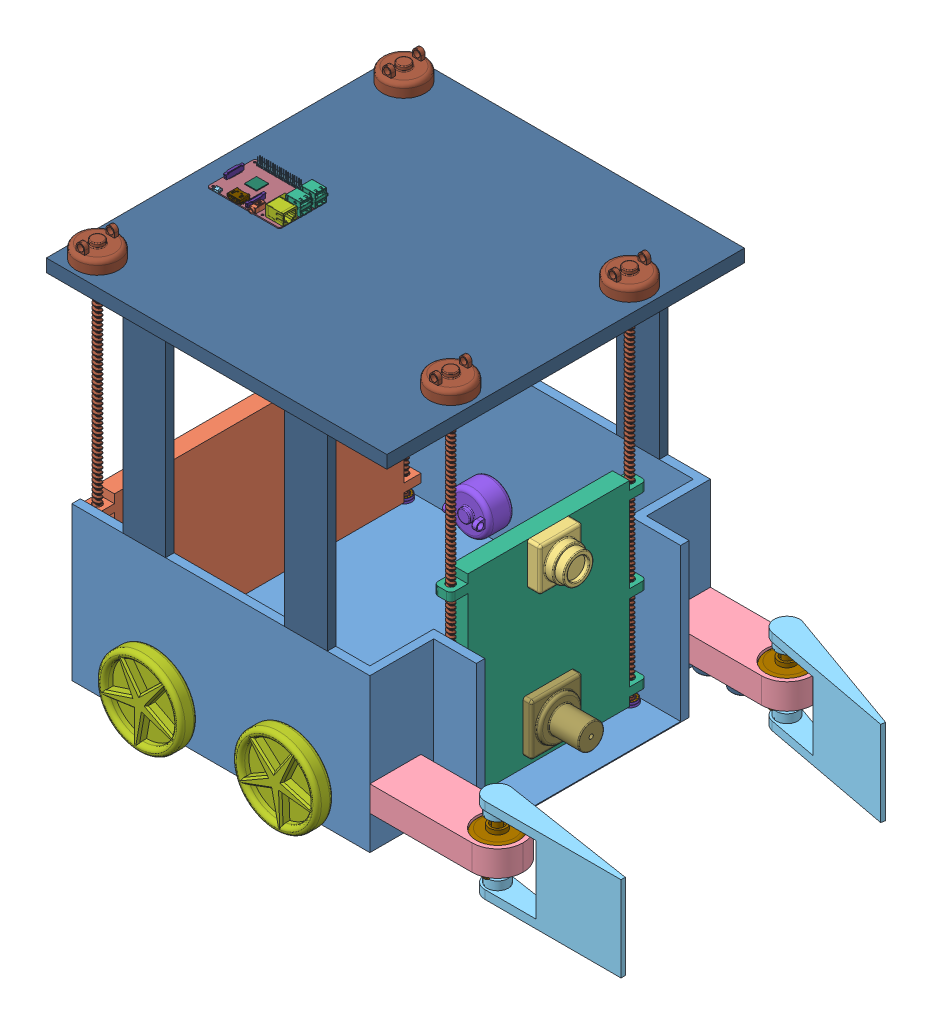
SolidWorks assembly BOT, configuration Default. Lengths in mm.
Overall size (650 473.67 464.94).
118 component instances, 28 part files, 77 mates.
Components (placement in the parent):
- Base-1: Base [Default] at origin size (400 180 400)
- Back-1: Back [Default] at (-175 95.5 0) size (20 179 380)
- Camera-2: Camera [Default] at (185 211 0) size (35 50 50)
- EP-1: EP [Default] at (175 55 170) size (150 30 60)
- EP-2: EP [Default] at (175 55 -170) size (150 30 60)
- Flap-1: Flap [Default] at (295 5 170) size (175 100 30)
- Flap-2: Flap [Default] at (295 5 -170) x (0.982637 0 0.185541) z (-0.185541 0 0.982637) size (175 100 30)
- Front-1: Front [Default] at (165 121 0) size (20 230 230)
- Wheel-1: Wheel [Default] at (-65 47 232) x (-0.85503 -0.518579 0) z (0 0 -1) size (100 100 25.47)
- Wheel-2: Wheel [Default] at (95 47 232) x (-0.730595 -0.682811 0) z (0 0 -1) size (100 100 25.47)
- Wheel-3: Wheel [Default] at (95 47 -232) x (0.960603 -0.277926 0) z (0 0 1) size (100 100 25.47)
- Wheel-4: Wheel [Default] at (-65 47 -232) x (0.992245 -0.124298 0) z (0 0 1) size (100 100 25.47)
- Motor-1: Motor [Default] at (-65 47 155) x (0 1 0) z (0 0 1) size (50 50 70)
- Motor-2: Motor [Default] at (95 47 155) x (0 -1 0) z (0 0 1) size (50 50 70)
- Motor-3: Motor [Default] at (95 47 -155) x (0 -1 0) z (0 0 -1) size (50 50 70)
- Motor-4: Motor [Default] at (-65 47 -155) x (0 -1 0) z (0 0 -1) size (50 50 70)
- Motor Double-1: Motor Double [Default] at (295 40 170) x (0.968172 0 -0.250286) z (0 1 0) size (50 50 70)
- Motor Double-2: Motor Double [Default] at (295 40 -170) x (1 0 0) z (0 1 0) size (50 50 70)
- Part Base-1: Part Base [Default] at (5 410 0) size (400 245 420)
- Motor Long-1: Motor Long [Default] at (175 440 -105) x (-1 0 0) z (0 -1 0) size (50 50 448)
- Motor Long-2: Motor Long [Default] at (-165 440 180) x (-1 0 0) z (0 -1 0) size (50 50 448)
- Motor Long-3: Motor Long [Default] at (-165 440 -180) x (-1 0 0) z (0 -1 0) size (50 50 448)
- Motor Long-4: Motor Long [Default] at (175 440 105) x (-1 0 0) z (0 -1 0) size (50 50 448)
- LIDAR-1: LIDAR [Default] at (185 48 0) size (50 60 60)
- RaspberryPi-1: RaspberryPi [Default] at (-127.6161 428.3 18) size (89.62 18.75 58.3)
  - RaspberryPi(2)^RaspberryPi-1: RaspberryPi(2)^RaspberryPi [Default] at origin size (89.62 18.75 58.3) (virtual)
    - Mainboard2^RaspberryPi(2)_RaspberryPi-1: Mainboard2^RaspberryPi(2)_RaspberryPi [Default] at origin size (85 1.3 56) (virtual)
    - GPIO^RaspberryPi(2)_RaspberryPi-1: GPIO^RaspberryPi(2)_RaspberryPi [Default] at (-11.37 0 -24.5) x (0 0 1) z (-1 0 0) size (5 11.5 50.8) (virtual)
    - Processor^RaspberryPi(2)_RaspberryPi-1: Processor^RaspberryPi(2)_RaspberryPi [Default] at (-15.5 0 -3) x (0 0 1) z (-1 0 0) size (14 1 14) (virtual)
    - GPU^RaspberryPi(2)_RaspberryPi-1: GPU^RaspberryPi(2)_RaspberryPi [Default] at (15.25 0 -5.75) x (0 0 1) z (-1 0 0) size (9.1 1 9.1) (virtual)
    - CameraAssembly^RaspberryPi(2)_RaspberryPi-1: CameraAssembly^RaspberryPi(2)_RaspberryPi [Default] at (10.0885 -2.9159 16.55) x (-1 0 0) z (0 0 -1) size (5.01 5.51 22.11) (virtual)
    - CameraAssembly^RaspberryPi(2)_RaspberryPi-2: CameraAssembly^RaspberryPi(2)_RaspberryPi [Default] at (-46.3885 -2.9159 0) size (5.01 5.51 22.11) (virtual)
    - HDMI^RaspberryPi(2)_RaspberryPi-1: HDMI^RaspberryPi(2)_RaspberryPi [Default] at (-10.2 0.27 29.3) size (15.04 8.38 12.15) (virtual)
    - RAM^RaspberryPi(2)_RaspberryPi-1: RAM^RaspberryPi(2)_RaspberryPi [Default] at (0.5 -2.3 -6) x (0 0 1) z (-1 0 0) size (12 1 12) (virtual)
    - Audio^RaspberryPi(2)_RaspberryPi-1: Audio^RaspberryPi(2)_RaspberryPi [Default] at (10.9 0.15 21.75) size (7 6 14.8) (virtual)
    - MicroSDSocket^RaspberryPi(2)_RaspberryPi-1: MicroSDSocket^RaspberryPi(2)_RaspberryPi [Default] at (-34.5 -1.3 -0.7) x (0 0 -1) z (-1 0 0) size (13 1.3 14) (virtual)
    - MicroSD^RaspberryPi(2)_RaspberryPi-1: MicroSD^RaspberryPi(2)_RaspberryPi [Default] at (-37 -2.3 0.1) x (0 0 1) z (-1 0 0) size (11.01 1 15) (virtual)
    - micro USB2^RaspberryPi(2)_RaspberryPi-1: micro USB2^RaspberryPi(2)_RaspberryPi [Default] at (-17.2704 -5.0969 44.9026) size (7.98 2.93 5.58) (virtual)
    - usb double^RaspberryPi(2)_RaspberryPi-1: usb double^RaspberryPi(2)_RaspberryPi [Default] at (30.38 -0.09 -18.85) x (0 0 -1) z (1 0 0) size (15.6 18.75 17.92) (virtual)
    - usb double^RaspberryPi(2)_RaspberryPi-2: usb double^RaspberryPi(2)_RaspberryPi [Default] at (30.38 -0.09 -1.25) x (0 0 -1) z (1 0 0) size (15.6 18.75 17.92) (virtual)
    - RJ45-LED^RaspberryPi(2)_RaspberryPi-1: RJ45-LED^RaspberryPi(2)_RaspberryPi [Default] at (34.11 7.4 17.348) x (1 0 0) z (0 -1 0) size (21.3 18 14.1) (virtual)
- Bearing-1: Bearing [Default] at (-165 1 -180) size (18 5 18)
  - Bearing ring-2: Bearing ring [Default] at origin size (18 5 18)
  - Bearing roller-16: Bearing roller [Default] at (6.5617 0.5 -1.5833) x (-0.193213 0 -0.981157) z (0.981157 0 -0.193213) size (2.5 4.5 2.5)
  - Bearing roller-17: Bearing roller [Default] at (5.5466 0.5 -3.8467) x (-0.5346 0 -0.845105) z (0.845105 0 -0.5346) size (2.5 4.5 2.5)
  - Bearing roller-18: Bearing roller [Default] at (3.7825 0.5 -5.5906) x (-0.803787 0 -0.594917) z (0.594917 0 -0.803787) size (2.5 4.5 2.5)
  - Bearing roller-19: Bearing roller [Default] at (1.5075 0.5 -6.5795) x (-0.964418 0 -0.264382) z (0.264382 0 -0.964418) size (2.5 4.5 2.5)
  - Bearing roller-20: Bearing roller [Default] at (-0.9711 0.5 -6.6798) x (-0.994799 0 0.101859) z (-0.101859 0 -0.994799) size (2.5 4.5 2.5)
  - Bearing roller-21: Bearing roller [Default] at (-3.3185 0.5 -5.8779) x (-0.890827 0 0.454343) z (-0.454343 0 -0.890827) size (2.5 4.5 2.5)
  - Bearing roller-22: Bearing roller [Default] at (-5.2178 0.5 -4.2822) x (-0.666544 0 0.745466) z (-0.745466 0 -0.666544) size (2.5 4.5 2.5)
  - Bearing roller-23: Bearing roller [Default] at (-6.4124 0.5 -2.1081) x (-0.35224 0 0.93591) z (-0.93591 0 -0.35224) size (2.5 4.5 2.5)
  - Bearing roller-24: Bearing roller [Default] at (-6.7409 0.5 0.3506) x (0.009636 0 0.999954) z (-0.999954 0 0.009636) size (2.5 4.5 2.5)
  - Bearing roller-25: Bearing roller [Default] at (-6.159 0.5 2.762) x (0.37021 0 0.928948) z (-0.928948 0 0.37021) size (2.5 4.5 2.5)
  - Bearing roller-26: Bearing roller [Default] at (-4.7454 0.5 4.8004) x (0.680785 0 0.732483) z (-0.732483 0 0.680785) size (2.5 4.5 2.5)
  - Bearing roller-27: Bearing roller [Default] at (-2.6908 0.5 6.1905) x (0.899417 0 0.437092) z (-0.437092 0 0.899417) size (2.5 4.5 2.5)
  - Bearing roller-28: Bearing roller [Default] at (-0.2728 0.5 6.7445) x (0.996577 0 0.082669) z (-0.082669 0 0.996577) size (2.5 4.5 2.5)
  - Bearing roller-29: Bearing roller [Default] at (2.182 0.5 6.3876) x (0.959144 0 -0.282918) z (0.282918 0 0.959144) size (2.5 4.5 2.5)
  - Bearing roller-30: Bearing roller [Default] at (4.3421 0.5 5.168) x (0.792173 0 -0.610296) z (0.610296 0 0.792173) size (2.5 4.5 2.5)
  - Bearing roller-31: Bearing roller [Default] at (5.9158 0.5 3.2505) x (0.518215 0 -0.85525) z (0.85525 0 0.518215) size (2.5 4.5 2.5)
  - Bearing roller-32: Bearing roller [Default] at (6.6905 0.5 0.894) x (0.174269 0 -0.984698) z (0.984698 0 0.174269) size (2.5 4.5 2.5)
- Bearing-2: Bearing [Default] at (175 1 105) size (18 5 18)
  - Bearing ring-2: Bearing ring [Default] at origin size (18 5 18)
  - Bearing roller-16: Bearing roller [Default] at (6.5617 0.5 -1.5833) x (-0.193213 0 -0.981157) z (0.981157 0 -0.193213) size (2.5 4.5 2.5)
  - Bearing roller-17: Bearing roller [Default] at (5.5466 0.5 -3.8467) x (-0.5346 0 -0.845105) z (0.845105 0 -0.5346) size (2.5 4.5 2.5)
  - Bearing roller-18: Bearing roller [Default] at (3.7825 0.5 -5.5906) x (-0.803787 0 -0.594917) z (0.594917 0 -0.803787) size (2.5 4.5 2.5)
  - Bearing roller-19: Bearing roller [Default] at (1.5075 0.5 -6.5795) x (-0.964418 0 -0.264382) z (0.264382 0 -0.964418) size (2.5 4.5 2.5)
  - Bearing roller-20: Bearing roller [Default] at (-0.9711 0.5 -6.6798) x (-0.994799 0 0.101859) z (-0.101859 0 -0.994799) size (2.5 4.5 2.5)
  - Bearing roller-21: Bearing roller [Default] at (-3.3185 0.5 -5.8779) x (-0.890827 0 0.454343) z (-0.454343 0 -0.890827) size (2.5 4.5 2.5)
  - Bearing roller-22: Bearing roller [Default] at (-5.2178 0.5 -4.2822) x (-0.666544 0 0.745466) z (-0.745466 0 -0.666544) size (2.5 4.5 2.5)
  - Bearing roller-23: Bearing roller [Default] at (-6.4124 0.5 -2.1081) x (-0.35224 0 0.93591) z (-0.93591 0 -0.35224) size (2.5 4.5 2.5)
  - Bearing roller-24: Bearing roller [Default] at (-6.7409 0.5 0.3506) x (0.009636 0 0.999954) z (-0.999954 0 0.009636) size (2.5 4.5 2.5)
  - Bearing roller-25: Bearing roller [Default] at (-6.159 0.5 2.762) x (0.37021 0 0.928948) z (-0.928948 0 0.37021) size (2.5 4.5 2.5)
  - Bearing roller-26: Bearing roller [Default] at (-4.7454 0.5 4.8004) x (0.680785 0 0.732483) z (-0.732483 0 0.680785) size (2.5 4.5 2.5)
  - Bearing roller-27: Bearing roller [Default] at (-2.6908 0.5 6.1905) x (0.899417 0 0.437092) z (-0.437092 0 0.899417) size (2.5 4.5 2.5)
  - Bearing roller-28: Bearing roller [Default] at (-0.2728 0.5 6.7445) x (0.996577 0 0.082669) z (-0.082669 0 0.996577) size (2.5 4.5 2.5)
  - Bearing roller-29: Bearing roller [Default] at (2.182 0.5 6.3876) x (0.959144 0 -0.282918) z (0.282918 0 0.959144) size (2.5 4.5 2.5)
  - Bearing roller-30: Bearing roller [Default] at (4.3421 0.5 5.168) x (0.792173 0 -0.610296) z (0.610296 0 0.792173) size (2.5 4.5 2.5)
  - Bearing roller-31: Bearing roller [Default] at (5.9158 0.5 3.2505) x (0.518215 0 -0.85525) z (0.85525 0 0.518215) size (2.5 4.5 2.5)
  - Bearing roller-32: Bearing roller [Default] at (6.6905 0.5 0.894) x (0.174269 0 -0.984698) z (0.984698 0 0.174269) size (2.5 4.5 2.5)
- Bearing-3: Bearing [Default] at (175 1 -105) size (18 5 18)
  - Bearing ring-2: Bearing ring [Default] at origin size (18 5 18)
  - Bearing roller-16: Bearing roller [Default] at (6.5617 0.5 -1.5833) x (-0.193213 0 -0.981157) z (0.981157 0 -0.193213) size (2.5 4.5 2.5)
  - Bearing roller-17: Bearing roller [Default] at (5.5466 0.5 -3.8467) x (-0.5346 0 -0.845105) z (0.845105 0 -0.5346) size (2.5 4.5 2.5)
  - Bearing roller-18: Bearing roller [Default] at (3.7825 0.5 -5.5906) x (-0.803787 0 -0.594917) z (0.594917 0 -0.803787) size (2.5 4.5 2.5)
  - Bearing roller-19: Bearing roller [Default] at (1.5075 0.5 -6.5795) x (-0.964418 0 -0.264382) z (0.264382 0 -0.964418) size (2.5 4.5 2.5)
  - Bearing roller-20: Bearing roller [Default] at (-0.9711 0.5 -6.6798) x (-0.994799 0 0.101859) z (-0.101859 0 -0.994799) size (2.5 4.5 2.5)
  - Bearing roller-21: Bearing roller [Default] at (-3.3185 0.5 -5.8779) x (-0.890827 0 0.454343) z (-0.454343 0 -0.890827) size (2.5 4.5 2.5)
  - Bearing roller-22: Bearing roller [Default] at (-5.2178 0.5 -4.2822) x (-0.666544 0 0.745466) z (-0.745466 0 -0.666544) size (2.5 4.5 2.5)
  - Bearing roller-23: Bearing roller [Default] at (-6.4124 0.5 -2.1081) x (-0.35224 0 0.93591) z (-0.93591 0 -0.35224) size (2.5 4.5 2.5)
  - Bearing roller-24: Bearing roller [Default] at (-6.7409 0.5 0.3506) x (0.009636 0 0.999954) z (-0.999954 0 0.009636) size (2.5 4.5 2.5)
  - Bearing roller-25: Bearing roller [Default] at (-6.159 0.5 2.762) x (0.37021 0 0.928948) z (-0.928948 0 0.37021) size (2.5 4.5 2.5)
  - Bearing roller-26: Bearing roller [Default] at (-4.7454 0.5 4.8004) x (0.680785 0 0.732483) z (-0.732483 0 0.680785) size (2.5 4.5 2.5)
  - Bearing roller-27: Bearing roller [Default] at (-2.6908 0.5 6.1905) x (0.899417 0 0.437092) z (-0.437092 0 0.899417) size (2.5 4.5 2.5)
  - Bearing roller-28: Bearing roller [Default] at (-0.2728 0.5 6.7445) x (0.996577 0 0.082669) z (-0.082669 0 0.996577) size (2.5 4.5 2.5)
  - Bearing roller-29: Bearing roller [Default] at (2.182 0.5 6.3876) x (0.959144 0 -0.282918) z (0.282918 0 0.959144) size (2.5 4.5 2.5)
  - Bearing roller-30: Bearing roller [Default] at (4.3421 0.5 5.168) x (0.792173 0 -0.610296) z (0.610296 0 0.792173) size (2.5 4.5 2.5)
  - Bearing roller-31: Bearing roller [Default] at (5.9158 0.5 3.2505) x (0.518215 0 -0.85525) z (0.85525 0 0.518215) size (2.5 4.5 2.5)
  - Bearing roller-32: Bearing roller [Default] at (6.6905 0.5 0.894) x (0.174269 0 -0.984698) z (0.984698 0 0.174269) size (2.5 4.5 2.5)
- Bearing-4: Bearing [Default] at (-165 1 180) size (18 5 18)
  - Bearing ring-2: Bearing ring [Default] at origin size (18 5 18)
  - Bearing roller-16: Bearing roller [Default] at (6.5617 0.5 -1.5833) x (-0.193213 0 -0.981157) z (0.981157 0 -0.193213) size (2.5 4.5 2.5)
  - Bearing roller-17: Bearing roller [Default] at (5.5466 0.5 -3.8467) x (-0.5346 0 -0.845105) z (0.845105 0 -0.5346) size (2.5 4.5 2.5)
  - Bearing roller-18: Bearing roller [Default] at (3.7825 0.5 -5.5906) x (-0.803787 0 -0.594917) z (0.594917 0 -0.803787) size (2.5 4.5 2.5)
  - Bearing roller-19: Bearing roller [Default] at (1.5075 0.5 -6.5795) x (-0.964418 0 -0.264382) z (0.264382 0 -0.964418) size (2.5 4.5 2.5)
  - Bearing roller-20: Bearing roller [Default] at (-0.9711 0.5 -6.6798) x (-0.994799 0 0.101859) z (-0.101859 0 -0.994799) size (2.5 4.5 2.5)
  - Bearing roller-21: Bearing roller [Default] at (-3.3185 0.5 -5.8779) x (-0.890827 0 0.454343) z (-0.454343 0 -0.890827) size (2.5 4.5 2.5)
  - Bearing roller-22: Bearing roller [Default] at (-5.2178 0.5 -4.2822) x (-0.666544 0 0.745466) z (-0.745466 0 -0.666544) size (2.5 4.5 2.5)
  - Bearing roller-23: Bearing roller [Default] at (-6.4124 0.5 -2.1081) x (-0.35224 0 0.93591) z (-0.93591 0 -0.35224) size (2.5 4.5 2.5)
  - Bearing roller-24: Bearing roller [Default] at (-6.7409 0.5 0.3506) x (0.009636 0 0.999954) z (-0.999954 0 0.009636) size (2.5 4.5 2.5)
  - Bearing roller-25: Bearing roller [Default] at (-6.159 0.5 2.762) x (0.37021 0 0.928948) z (-0.928948 0 0.37021) size (2.5 4.5 2.5)
  - Bearing roller-26: Bearing roller [Default] at (-4.7454 0.5 4.8004) x (0.680785 0 0.732483) z (-0.732483 0 0.680785) size (2.5 4.5 2.5)
  - Bearing roller-27: Bearing roller [Default] at (-2.6908 0.5 6.1905) x (0.899417 0 0.437092) z (-0.437092 0 0.899417) size (2.5 4.5 2.5)
  - Bearing roller-28: Bearing roller [Default] at (-0.2728 0.5 6.7445) x (0.996577 0 0.082669) z (-0.082669 0 0.996577) size (2.5 4.5 2.5)
  - Bearing roller-29: Bearing roller [Default] at (2.182 0.5 6.3876) x (0.959144 0 -0.282918) z (0.282918 0 0.959144) size (2.5 4.5 2.5)
  - Bearing roller-30: Bearing roller [Default] at (4.3421 0.5 5.168) x (0.792173 0 -0.610296) z (0.610296 0 0.792173) size (2.5 4.5 2.5)
  - Bearing roller-31: Bearing roller [Default] at (5.9158 0.5 3.2505) x (0.518215 0 -0.85525) z (0.85525 0 0.518215) size (2.5 4.5 2.5)
  - Bearing roller-32: Bearing roller [Default] at (6.6905 0.5 0.894) x (0.174269 0 -0.984698) z (0.984698 0 0.174269) size (2.5 4.5 2.5)
- USS-1: USS [Default] at (225 40 -170) x (-1 0 0) z (0 0 1) size (80 20 40)
Mates (geometry in assembly coordinates):
- Concentric1: concentric anti-aligned: cylinder of Base-1 through (95 47 -200) axis (0 0 1) radius 10; cylinder of Wheel-3 through (95 47 -207) axis (0 0 -1) radius 9
- Concentric2: concentric anti-aligned: cylinder of Base-1 through (-65 47 -200) axis (0 0 1) radius 10; cylinder of Wheel-4 through (-65 47 -207) axis (0 0 -1) radius 9
- Concentric3: concentric aligned: cylinder of Base-1 through (95 47 -200) axis (0 0 1) radius 10; cylinder of Wheel-2 through (95 47 207) axis (0 0 1) radius 9
- Concentric4: concentric aligned: cylinder of Base-1 through (-65 47 -200) axis (0 0 1) radius 10; cylinder of Wheel-1 through (-65 47 207) axis (0 0 1) radius 9
- Distance9: distance = 90 mm aligned: plane of Camera-2 through (200 236 25) normal (0 0 1); plane of Front-1 through (185 236 115) normal (0 0 1)
- Coincident13: coincident aligned: plane of Camera-2 through (200 236 25) normal (0 1 0); plane of Front-1 through (185 236 115) normal (0 1 0)
- Coincident14: coincident anti-aligned: plane of Camera-2 through (185 211 0) normal (-1 0 0); plane of Front-1 through (185 121 0) normal (1 0 0)
- Coincident17: coincident aligned: plane of Base-1 through (0 180 200) normal (0 0 1); plane of EP-1 through (325 70 200) normal (0 0 1)
- Distance12: distance = 40 mm aligned: plane of Base-1 through (0 0 0) normal (0 -1 0); plane of EP-1 through (325 40 200) normal (0 -1 0)
- Coincident19: coincident anti-aligned: plane of Base-1 through (175 180 0) normal (1 0 0); plane of EP-1 through (175 55 170) normal (-1 0 0)
- Coincident20: coincident aligned: plane of Base-1 through (0 180 -200) normal (0 0 -1); plane of EP-2 through (325 70 -200) normal (0 0 -1)
- Distance13: distance = 40 mm aligned: plane of Base-1 through (0 0 0) normal (0 -1 0); plane of EP-2 through (325 40 -140) normal (0 -1 0)
- Coincident22: coincident anti-aligned: plane of Base-1 through (175 180 0) normal (1 0 0); plane of EP-2 through (175 55 -170) normal (-1 0 0)
- Distance14: distance = 25 mm anti-aligned: plane of Flap-1 through (295 15 170) normal (0 1 0); plane of EP-1 through (325 40 200) normal (0 -1 0)
- Distance15: distance = 25 mm anti-aligned: plane of EP-2 through (325 40 -140) normal (0 -1 0); plane of Flap-2 through (295 15 -170) normal (0 1 0)
- Coincident25: coincident aligned: plane of Base-1 through (-175 180 0) normal (-1 0 0); plane of Back-1 through (-175 95.5 0) normal (-1 0 0)
- Coincident28: coincident aligned: plane of Base-1 through (165 1 0) normal (-1 0 0); plane of Front-1 through (165 121 0) normal (-1 0 0)
- LimitDistance1: limit distance = 5 mm anti-aligned: plane of Base-1 through (0 1 0) normal (0 1 0); plane of Back-1 through (-155 6 190) normal (0 -1 0)
- LimitDistance2: limit distance = 5 mm anti-aligned: plane of Base-1 through (0 1 0) normal (0 1 0); plane of Front-1 through (185 6 115) normal (0 -1 0)
- LimitAngle1: limit planar angle = 0 rad aligned: plane of EP-1 through (325 70 200) normal (0 0 1); plane of Flap-1 through (295 55 185) normal (0 0 1)
- LimitAngle2: limit planar angle = 0.341619 rad aligned: plane of EP-2 through (325 70 -200) normal (0 0 -1); plane of Flap-2 through (299.9649 55 -183.9638) normal (0.335013 0 -0.942214)
- Concentric7: concentric anti-aligned: cylinder of Base-1 through (95 47 -200) axis (0 0 1) radius 10; cylinder of Motor-2 through (95 47 205) axis (0 0 -1) radius 10
- Concentric8: concentric anti-aligned: cylinder of Base-1 through (-65 47 -200) axis (0 0 1) radius 10; cylinder of Motor-1 through (-65 47 205) axis (0 0 -1) radius 10
- Concentric9: concentric aligned: cylinder of Base-1 through (-65 47 -200) axis (0 0 1) radius 10; cylinder of Motor-4 through (-65 47 -205) axis (0 0 1) radius 10
- Concentric11: concentric aligned: cylinder of Base-1 through (95 47 -200) axis (0 0 1) radius 10; cylinder of Motor-3 through (95 47 -205) axis (0 0 1) radius 10
- Distance18: distance = 5 mm anti-aligned: plane of Base-1 through (0 1 190) normal (0 0 -1); plane of Motor-1 through (-65 47 185) normal (0 0 1)
- Distance19: distance = 5 mm anti-aligned: plane of Base-1 through (0 1 190) normal (0 0 -1); plane of Motor-2 through (95 47 185) normal (0 0 1)
- Distance20: distance = 5 mm anti-aligned: plane of Base-1 through (0 1 -190) normal (0 0 1); plane of Motor-3 through (95 47 -185) normal (0 0 -1)
- Distance21: distance = 5 mm anti-aligned: plane of Base-1 through (0 1 -190) normal (0 0 1); plane of Motor-4 through (-65 47 -185) normal (0 0 -1)
- Parallel1: parallel aligned: plane of Base-1 through (0 1 0) normal (0 1 0); plane of Motor-4 through (-45 52 -145) normal (0 1 0)
- Parallel2: parallel aligned: plane of Base-1 through (0 1 0) normal (0 1 0); plane of Motor-3 through (115 52 -145) normal (0 1 0)
- Parallel3: parallel aligned: plane of Base-1 through (0 1 0) normal (0 1 0); plane of Motor-2 through (110 52 145) normal (0 1 0)
- Parallel4: parallel aligned: plane of Base-1 through (0 1 0) normal (0 1 0); plane of Motor-1 through (-80 52 145) normal (0 1 0)
- Distance23: distance = 2 mm anti-aligned: plane of Wheel-4 through (-65 47 -207) normal (0 0 1); plane of Motor-4 through (-65 47 -205) normal (0 0 -1)
- Distance24: distance = 2 mm anti-aligned: plane of Motor-3 through (95 47 -205) normal (0 0 -1); plane of Wheel-3 through (95 47 -207) normal (0 0 1)
- Distance25: distance = 2 mm anti-aligned: plane of Wheel-1 through (-65 47 207) normal (0 0 -1); plane of Motor-1 through (-65 47 205) normal (0 0 1)
- Distance26: distance = 2 mm anti-aligned: plane of Wheel-2 through (95 47 207) normal (0 0 -1); plane of Motor-2 through (95 47 205) normal (0 0 1)
- Concentric12: concentric anti-aligned: cylinder of EP-1 through (295 -30.7107 170) axis (0 1 0) radius 25; cylinder of Motor Double-1 through (295 70 170) axis (0 -1 0) radius 25
- Coincident47: coincident aligned: plane of EP-1 through (325 40 200) normal (0 -1 0); plane of Motor Double-1 through (295 40 170) normal (0 -1 0)
- Concentric13: concentric anti-aligned: cylinder of EP-2 through (295 -30.7107 -170) axis (0 1 0) radius 25; cylinder of Motor Double-2 through (295 70 -170) axis (0 -1 0) radius 25
- Coincident48: coincident aligned: plane of EP-2 through (325 40 -140) normal (0 -1 0); plane of Motor Double-2 through (295 40 -170) normal (0 -1 0)
- Concentric14: concentric aligned: cylinder of Flap-1 through (295 20 170) axis (0 1 0) radius 5; cylinder of Motor Double-1 through (295 20 170) axis (0 1 0) radius 5
- Concentric15: concentric aligned: cylinder of Flap-2 through (295 20 -170) axis (0 1 0) radius 5; cylinder of Motor Double-2 through (295 20 -170) axis (0 1 0) radius 5
- Concentric16: concentric aligned: cylinder of Back-1 through (-165 1.8579 180) axis (0 1 0) radius 5; cylinder of Motor Long-2 through (-165 2 180) axis (0 1 0) radius 4.5
- Concentric17: concentric aligned: cylinder of Back-1 through (-165 1.8579 -180) axis (0 1 0) radius 5; cylinder of Motor Long-3 through (-165 2 -180) axis (0 1 0) radius 4.5
- Concentric18: concentric aligned: cylinder of Front-1 through (175 1.8579 105) axis (0 1 0) radius 5; cylinder of Motor Long-4 through (175 2 105) axis (0 1 0) radius 4.5
- Concentric19: concentric aligned: cylinder of Front-1 through (175 1.8579 -105) axis (0 1 0) radius 5; cylinder of Motor Long-1 through (175 2 -105) axis (0 1 0) radius 4.5
- Concentric20: concentric aligned: cylinder of Part Base-1 through (-165 339.2893 180) axis (0 1 0) radius 25; cylinder of Motor Long-2 through (-165 410 180) axis (0 1 0) radius 25
- Concentric21: concentric aligned: cylinder of Part Base-1 through (-165 339.2893 -180) axis (0 1 0) radius 25; cylinder of Motor Long-3 through (-165 410 -180) axis (0 1 0) radius 25
- Concentric22: concentric aligned: cylinder of Part Base-1 through (175 339.2893 105) axis (0 1 0) radius 25; cylinder of Motor Long-4 through (175 410 105) axis (0 1 0) radius 25
- Concentric23: concentric aligned: cylinder of Part Base-1 through (175 339.2893 -105) axis (0 1 0) radius 25; cylinder of Motor Long-1 through (175 410 -105) axis (0 1 0) radius 25
- Coincident49: coincident aligned: plane of Part Base-1 through (5 410 0) normal (0 -1 0); plane of Motor Long-4 through (175 410 105) normal (0 -1 0)
- Coincident50: coincident aligned: plane of Part Base-1 through (5 410 0) normal (0 -1 0); plane of Motor Long-1 through (175 410 -105) normal (0 -1 0)
- Coincident51: coincident aligned: plane of Part Base-1 through (5 410 0) normal (0 -1 0); plane of Motor Long-3 through (-165 410 -180) normal (0 -1 0)
- Coincident52: coincident aligned: plane of Part Base-1 through (5 410 0) normal (0 -1 0); plane of Motor Long-2 through (-165 410 180) normal (0 -1 0)
- Coincident53: coincident anti-aligned: plane of Base-1 through (0 180 0) normal (0 1 0); plane of Part Base-1 through (5 180 0) normal (0 -1 0)
- Parallel5: parallel aligned: plane of Part Base-1 through (-195 425 -210) normal (-1 0 0); plane of Motor Long-3 through (-170 450 -160) normal (-1 0 0)
- Parallel6: parallel aligned: plane of Part Base-1 through (-195 425 -210) normal (-1 0 0); plane of Motor Long-2 through (-170 450 200) normal (-1 0 0)
- Parallel7: parallel aligned: plane of Part Base-1 through (205 425 -210) normal (1 0 0); plane of Motor Long-4 through (180 450 90) normal (1 0 0)
- Parallel8: parallel aligned: plane of Part Base-1 through (205 425 -210) normal (1 0 0); plane of Motor Long-1 through (180 450 -120) normal (1 0 0)
- Coincident58: coincident aligned: plane of Base-1 through (0 180 200) normal (0 0 1); plane of Part Base-1 through (75 180 200) normal (0 0 1)
- Coincident59: coincident anti-aligned: plane of Front-1 through (185 121 0) normal (1 0 0); plane of LIDAR-1 through (185 48 0) normal (-1 0 0)
- Distance27: distance = 12 mm aligned: plane of Front-1 through (185 6 115) normal (0 -1 0); plane of LIDAR-1 through (195 18 30) normal (0 -1 0)
- Distance28: distance = 65 mm aligned: plane of Front-1 through (165 121 95) normal (0 0 1); plane of LIDAR-1 through (195 78 30) normal (0 0 1)
- Distance29: distance = 1 mm anti-aligned: plane of Part Base-1 through (5 425 0) normal (0 1 0); plane of RaspberryPi-1/RaspberryPi(2)^RaspberryPi-1/RAM^RaspberryPi(2)_RaspberryPi-1 through (-127.1161 426 12) normal (0 -1 0)
- Distance30: distance = 200 mm aligned: plane of Part Base-1 through (-195 425 -210) normal (0 0 -1); plane of RaspberryPi-1/RaspberryPi(2)^RaspberryPi-1/Mainboard2^RaspberryPi(2)_RaspberryPi-1 through (-87.6161 427 -10) normal (0 0 -1)
- Concentric24: concentric anti-aligned: cylinder of Motor Long-3 through (-165 2 -180) axis (0 1 0) radius 4.5; cylinder of Bearing-1/Bearing ring-2 through (-165 6 -180) axis (0 -1 0) radius 5
- Coincident60: coincident anti-aligned: plane of Base-1 through (0 1 0) normal (0 1 0); plane of Bearing-1/Bearing ring-2 through (-165 1 -180) normal (0 -1 0)
- Concentric25: concentric anti-aligned: cylinder of Motor Long-2 through (-165 2 180) axis (0 1 0) radius 4.5; cylinder of Bearing-4/Bearing ring-2 through (-165 6 180) axis (0 -1 0) radius 5
- Coincident61: coincident anti-aligned: plane of Base-1 through (0 1 0) normal (0 1 0); plane of Bearing-4/Bearing ring-2 through (-165 1 180) normal (0 -1 0)
- Concentric26: concentric anti-aligned: cylinder of Motor Long-1 through (175 2 -105) axis (0 1 0) radius 4.5; cylinder of Bearing-3/Bearing ring-2 through (175 6 -105) axis (0 -1 0) radius 5
- Coincident62: coincident anti-aligned: plane of Base-1 through (0 1 0) normal (0 1 0); plane of Bearing-3/Bearing ring-2 through (175 1 -105) normal (0 -1 0)
- Concentric28: concentric anti-aligned: cylinder of Motor Long-4 through (175 2 105) axis (0 1 0) radius 4.5; cylinder of Bearing-2/Bearing ring-2 through (175 6 105) axis (0 -1 0) radius 5
- Coincident63: coincident anti-aligned: plane of Base-1 through (0 1 0) normal (0 1 0); plane of Bearing-2/Bearing ring-2 through (175 1 105) normal (0 -1 0)
- Coincident64: coincident anti-aligned: plane of EP-2 through (325 40 -140) normal (0 -1 0); plane of USS-1 through (225 40 -170) normal (0 1 0)
- Distance31: distance = 10 mm aligned: plane of USS-1 through (265 35 -190) normal (0 0 -1); plane of EP-2 through (325 70 -200) normal (0 0 -1)
- Distance32: distance = 10 mm anti-aligned: plane of Base-1 through (175 180 0) normal (1 0 0); plane of USS-1 through (185 35 -190) normal (-1 0 0)
